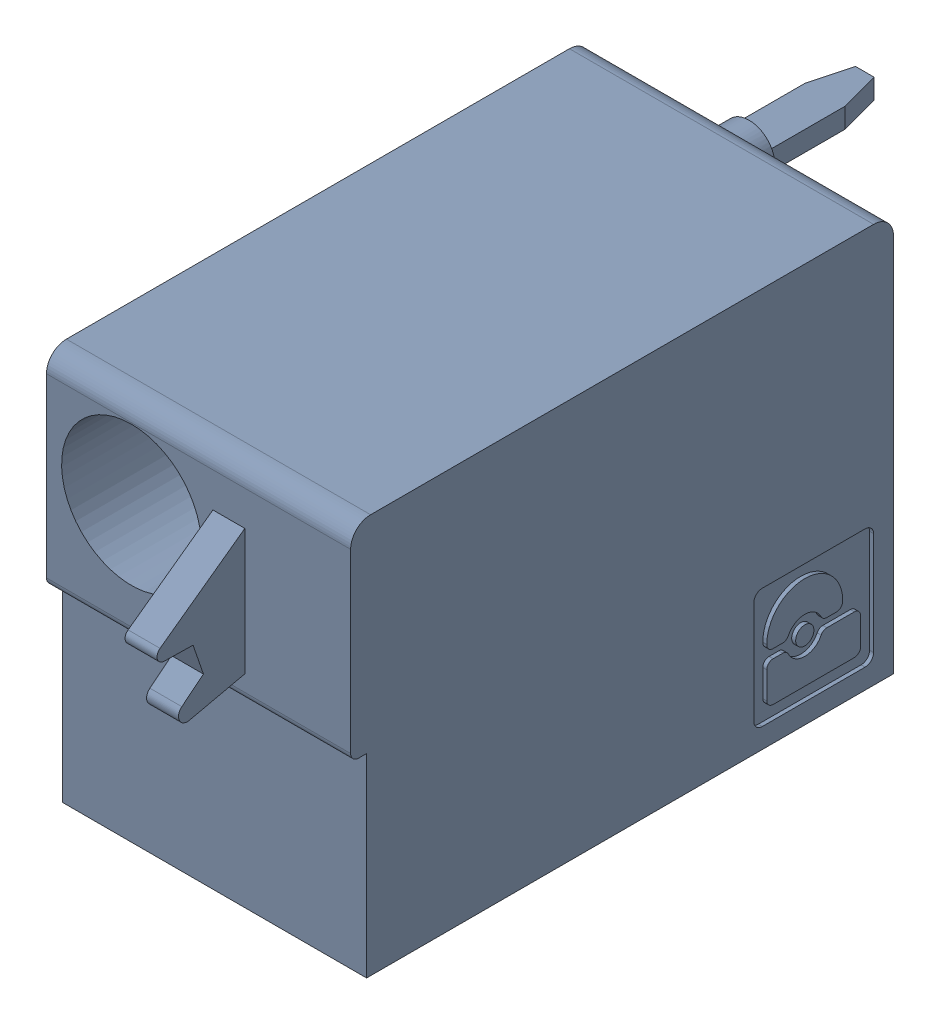
SolidWorks assembly J28, configuration Default. Lengths in mm.
Overall size (7.62 10 19.2).
2 component instances, 1 part files, 0 mates.
Components (placement in the parent):
- 1790487-1: 1790487 [Default] at (61.365 -15.67 -10.6) x (0 1 0) z (1 0 0) size (10 19.2 7.62)
  - ffkdsa1-v2-7.62-1: ffkdsa1-v2-7.62 [Default] at (-15.6914 -27.508 9.12) x (0 -1 0) z (0 0 1) size (19.2 10 7.62)
